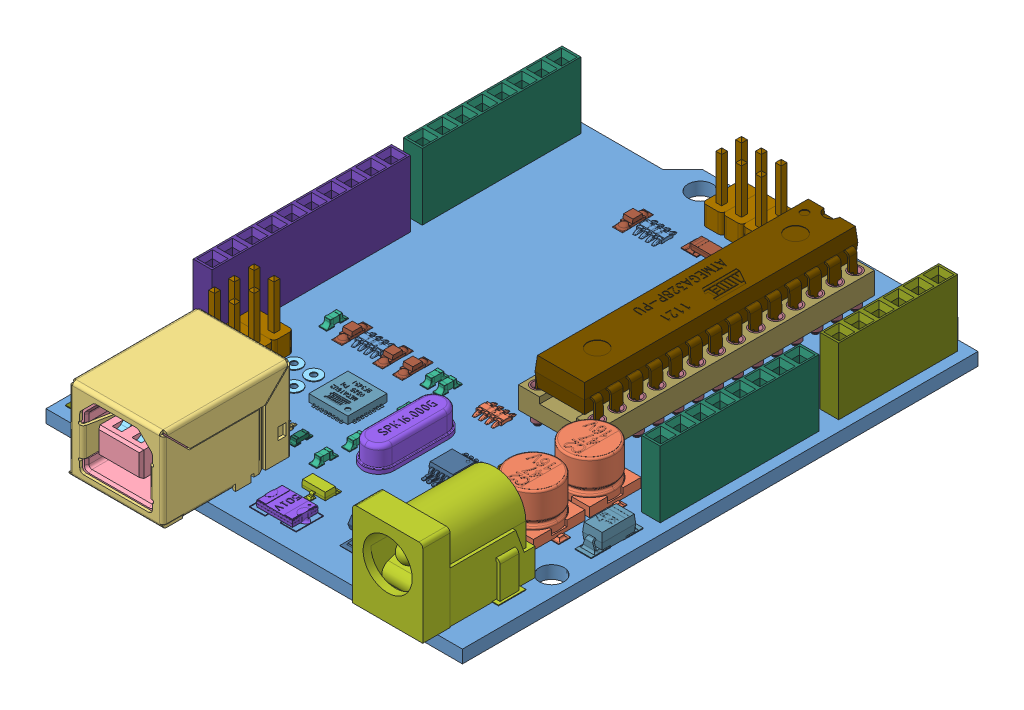
SolidWorks assembly arduino uno, configuration Default. Lengths in mm.
Overall size (53.34 15.25 74.93).
84 component instances, 35 part files, 0 mates.
Components (placement in the parent):
- unoboard blue-1: unoboard blue [Default] at origin size (53.34 1.65 68.58)
- 47uf CAP Dcase-1: 47uf CAP Dcase [Default] at (-9.4141 0 -18.4991) x (0 0 -1) z (1 0 0) size (6.6 5.81 8)
- USB SHELL-1: USB SHELL [Default] at (-38.02 0.43 6.35) size (13.72 15.2 16.51)
- USB core-1: USB core [Default] at (-38.02 0.43 6.35) size (11.3 10.68 15.75)
- usb top contact-1: usb top contact [Default] at (-36.77 6.52 5.97) size (1 9.67 13.76)
- usb btm contact-1: usb btm contact [Default] at (-36.77 4.84 5.97) size (1 6.84 11.76)
- usb btm contact-2: usb btm contact [Default] at (-39.27 4.84 5.97) size (1 6.84 11.76)
- usb top contact-2: usb top contact [Default] at (-39.27 6.52 5.97) size (1 9.67 13.76)
- power jack-1: power jack [Default] at (-7.675 0 1.905) size (11.2 15.2 15.9)
- 47uf CAP Dcase-2: 47uf CAP Dcase [Default] at (-9.4141 0 -25.7132) x (0 0 -1) z (1 0 0) size (6.6 5.81 8)
- crystal-1: crystal [Default] at (-26.162 0 -18.923) x (1 0 0) z (0 0 -1) size (4 5 11)
- 2pin_header__02-1: 2pin_header__02 [Default] at (-46.23 0 -15.75) size (5 11.75 2.54)
- nano - reg-1: nano - reg [Default] at (-17.399 0 -7.747) size (6.5 1.69 8.3)
- led-1: led [Default] at (-34.29 0 -27.94) x (0 0 1) z (-1 0 0) size (4 0.9 1.55)
- 2pin_header__02-2: 2pin_header__02 [Default] at (-30.43 0 -64.91) x (0 0 1) z (-1 0 0) size (5 11.75 2.54)
- dip28-1: dip28 [Default] at (-16.383 1.5 -46.355) x (0 0 -1) z (1 0 0) size (35.48 2.8 10.1)
- dip socket pin-1: dip socket pin [Default] at (-20.193 4.3 -62.865) x (0 0 -1) z (1 0 0) size (1.7 7.37 1.7)
- dip socket pin-2: dip socket pin [Default] at (-12.573 4.3 -62.865) x (0 0 -1) z (1 0 0) size (1.7 7.37 1.7)
- dip socket pin-3: dip socket pin [Default] at (-20.193 4.3 -60.325) x (0 0 -1) z (1 0 0) size (1.7 7.37 1.7)
- dip socket pin-4: dip socket pin [Default] at (-12.573 4.3 -60.325) x (0 0 -1) z (1 0 0) size (1.7 7.37 1.7)
- dip socket pin-5: dip socket pin [Default] at (-20.193 4.3 -57.785) x (0 0 -1) z (1 0 0) size (1.7 7.37 1.7)
- dip socket pin-6: dip socket pin [Default] at (-12.573 4.3 -57.785) x (0 0 -1) z (1 0 0) size (1.7 7.37 1.7)
- dip socket pin-7: dip socket pin [Default] at (-20.193 4.3 -55.245) x (0 0 -1) z (1 0 0) size (1.7 7.37 1.7)
- dip socket pin-8: dip socket pin [Default] at (-12.573 4.3 -55.245) x (0 0 -1) z (1 0 0) size (1.7 7.37 1.7)
- dip socket pin-9: dip socket pin [Default] at (-20.193 4.3 -52.705) x (0 0 -1) z (1 0 0) size (1.7 7.37 1.7)
- dip socket pin-10: dip socket pin [Default] at (-12.573 4.3 -52.705) x (0 0 -1) z (1 0 0) size (1.7 7.37 1.7)
- dip socket pin-11: dip socket pin [Default] at (-20.193 4.3 -50.165) x (0 0 -1) z (1 0 0) size (1.7 7.37 1.7)
- dip socket pin-12: dip socket pin [Default] at (-12.573 4.3 -50.165) x (0 0 -1) z (1 0 0) size (1.7 7.37 1.7)
- dip socket pin-13: dip socket pin [Default] at (-20.193 4.3 -47.625) x (0 0 -1) z (1 0 0) size (1.7 7.37 1.7)
- dip socket pin-14: dip socket pin [Default] at (-12.573 4.3 -47.625) x (0 0 -1) z (1 0 0) size (1.7 7.37 1.7)
- dip socket pin-15: dip socket pin [Default] at (-20.193 4.3 -45.085) x (0 0 -1) z (1 0 0) size (1.7 7.37 1.7)
- dip socket pin-16: dip socket pin [Default] at (-12.573 4.3 -45.085) x (0 0 -1) z (1 0 0) size (1.7 7.37 1.7)
- dip socket pin-17: dip socket pin [Default] at (-20.193 4.3 -42.545) x (0 0 -1) z (1 0 0) size (1.7 7.37 1.7)
- dip socket pin-18: dip socket pin [Default] at (-12.573 4.3 -42.545) x (0 0 -1) z (1 0 0) size (1.7 7.37 1.7)
- dip socket pin-19: dip socket pin [Default] at (-20.193 4.3 -40.005) x (0 0 -1) z (1 0 0) size (1.7 7.37 1.7)
- dip socket pin-20: dip socket pin [Default] at (-12.573 4.3 -40.005) x (0 0 -1) z (1 0 0) size (1.7 7.37 1.7)
- dip socket pin-21: dip socket pin [Default] at (-20.193 4.3 -37.465) x (0 0 -1) z (1 0 0) size (1.7 7.37 1.7)
- dip socket pin-22: dip socket pin [Default] at (-12.573 4.3 -37.465) x (0 0 -1) z (1 0 0) size (1.7 7.37 1.7)
- dip socket pin-23: dip socket pin [Default] at (-20.193 4.3 -34.925) x (0 0 -1) z (1 0 0) size (1.7 7.37 1.7)
- dip socket pin-24: dip socket pin [Default] at (-12.573 4.3 -34.925) x (0 0 -1) z (1 0 0) size (1.7 7.37 1.7)
- dip socket pin-25: dip socket pin [Default] at (-20.193 4.3 -32.385) x (0 0 -1) z (1 0 0) size (1.7 7.37 1.7)
- dip socket pin-26: dip socket pin [Default] at (-12.573 4.3 -32.385) x (0 0 -1) z (1 0 0) size (1.7 7.37 1.7)
- dip socket pin-27: dip socket pin [Default] at (-20.193 4.3 -29.845) x (0 0 -1) z (1 0 0) size (1.7 7.37 1.7)
- dip socket pin-28: dip socket pin [Default] at (-12.573 4.3 -29.845) x (0 0 -1) z (1 0 0) size (1.7 7.37 1.7)
- 2pin_header__02-3: 2pin_header__02 [Default] at (-27.89 0 -64.91) x (0 0 1) z (-1 0 0) size (5 11.75 2.54)
- 2pin_header__02-4: 2pin_header__02 [Default] at (-25.35 0 -64.91) x (0 0 1) z (-1 0 0) size (5 11.75 2.54)
- 2pin_header__02-5: 2pin_header__02 [Default] at (-46.23 0 -18.29) size (5 11.75 2.54)
- 2pin_header__02-6: 2pin_header__02 [Default] at (-46.23 0 -20.83) size (5 11.75 2.54)
- atmega16u2-1: atmega16u2 [Default] at (-34.671 0.06 -20) x (1 0 0) z (0 0 -1) size (5.5 1.01 5.5)
- led-2: led [Default] at (-36.83 0 -27.94) x (0 0 1) z (-1 0 0) size (4 0.9 1.55)
- led-3: led [Default] at (-42.037 0 -27.94) x (0 0 1) z (-1 0 0) size (4 0.9 1.55)
- led-4: led [Default] at (-36.576 0 -58.42) x (0 0 1) z (-1 0 0) size (4 0.9 1.55)
- 8 PORT HEADER-1: 8 PORT HEADER [Default] at (-50.8 0 -45.72) x (0 0 -1) z (1 0 0) size (20.32 10.51 2.41)
- 8 PORT HEADER-2: 8 PORT HEADER [Default] at (-2.54 0 -27.94) x (0 0 -1) z (1 0 0) size (20.32 10.51 2.41)
- 6 PORT HEADER-1: 6 PORT HEADER [Default] at (-2.54 0 -50.8) x (0 0 -1) z (1 0 0) size (15.24 10.51 2.41)
- 10 PORT HEADER-1: 10 PORT HEADER [Default] at (-50.8 0 -18.796) x (0 0 -1) z (1 0 0) size (25.4 10.51 2.41)
- ATMEL328P-1: ATMEL328P [Default] at (-16.383 4.3 -46.355) x (0 0 -1) z (1 0 0) size (35 7.27 7.87)
- 102 RESISTOR PACK-1: 102 RESISTOR PACK [Default] at (-33.782 0 -58.42) size (3.2 0.51 3)
- 102 RESISTOR PACK-2: 102 RESISTOR PACK [Default] at (-39.37 0 -27.94) size (3.2 0.51 3)
- 103 RESISTOR PACK-1: 103 RESISTOR PACK [Default] at (-23.876 0 -27.94) size (3.2 0.51 3)
- 220 RESISTOR PACK-1: 220 RESISTOR PACK [Default] at (-36.83 0 -12.827) size (3.2 0.51 3)
- 16mhz crystal - measured-1: 16mhz crystal - measured [Default] at (-24.892 0 -41.275) x (0 0 -1) z (1 0 0) size (3.4 0.8 2)
- PADS001-1: PADS001 [Default] at (-39.878 0.1 -18.288) x (-1 0 0) z (0 0 1) size (4.54 0.1 4.54)
- 603 cap on pad-1: 603 cap on pad [Default] at (-44.45 0 -27.94) x (0 0 -1) z (1 0 0) size (2.76 0.91 1.02)
- ssot3-1: ssot3 [Default] at (-26.5 0 -8.128) x (-1 0 0) z (0 0 -1) size (3 1.13 3.09)
- mf-msmf050-2-1: mf-msmf050-2 [Default] at (-26.5 0 -4.064) size (5.76 1.02 3.72)
- 603 cap on pad-2: 603 cap on pad [Default] at (-29.845 0 -27.94) x (0 0 -1) z (1 0 0) size (2.76 0.91 1.02)
- 603 cap on pad-3: 603 cap on pad [Default] at (-31.496 0 -27.94) x (0 0 -1) z (1 0 0) size (2.76 0.91 1.02)
- lmv358-1: lmv358 [Default] at (-15.24 0 -21.971) x (0 0 -1) z (1 0 0) size (3.7 1.4 2.9)
- 603 cap on pad-4: 603 cap on pad [Default] at (-15.24 0 -18.415) size (2.76 0.91 1.02)
- 603 cap on pad-5: 603 cap on pad [Default] at (-29.845 0 -12.065) x (0 0 1) z (-1 0 0) size (2.76 0.91 1.02)
- 603 cap on pad-6: 603 cap on pad [Default] at (-29.591 0 -22.352) x (0 0 1) z (-1 0 0) size (2.76 0.91 1.02)
- 603 cap on pad-7: 603 cap on pad [Default] at (-29.591 0 -16.002) x (0 0 1) z (-1 0 0) size (2.76 0.91 1.02)
- 603 cap on pad-8: 603 cap on pad [Default] at (-41.91 0 -12.7) x (0 0 1) z (-1 0 0) size (2.76 0.91 1.02)
- lp2985dgkr-1: lp2985dgkr [Default] at (-20.32 0 -19.05) x (0 0 -1) z (1 0 0) size (5.85 1.1 3)
- cd1206 diode-1: cd1206 diode [Default] at (-27.94 0 -59.436) x (0 0 -1) z (1 0 0) size (2.09 0.96 5)
- cd1206 diode-2: cd1206 diode [Default] at (-46.228 0 -13.081) x (0 0 1) z (-1 0 0) size (2.09 0.96 5)
- 603 resistor-1: 603 resistor [Default] at (-29.591 0 -19.05) x (0 0 1) z (-1 0 0) size (2.36 0.62 1.03)
- blm21-1: blm21 [Default] at (-45.085 0 -7.62) x (0 0 -1) z (1 0 0) size (2.78 0.95 1.32)
- m7 diode-1: m7 diode [Default] at (-2.794 0 -21.59) x (0 0 -1) z (1 0 0) size (6.66 2.35 2.5)
- MLC0603-1: MLC0603 [Default] at (-33.655 0 -12.827) x (0 0 -1) z (1 0 0) size (2.36 0.6 1.03)
- MLC0603-2: MLC0603 [Default] at (-39.37 0 -12.827) x (0 0 -1) z (1 0 0) size (2.36 0.6 1.03)
- RESET CORE-1: RESET CORE [Default] at (-49.403 0.1 -6.35) x (-1 0 0) z (0 0 -1) size (6.2 3.1 9.6)
- RESET-1: RESET [Default] at (-49.403 0.1 -6.35) x (0 0 1) z (-1 0 0) size (7.3 2 6.2)
